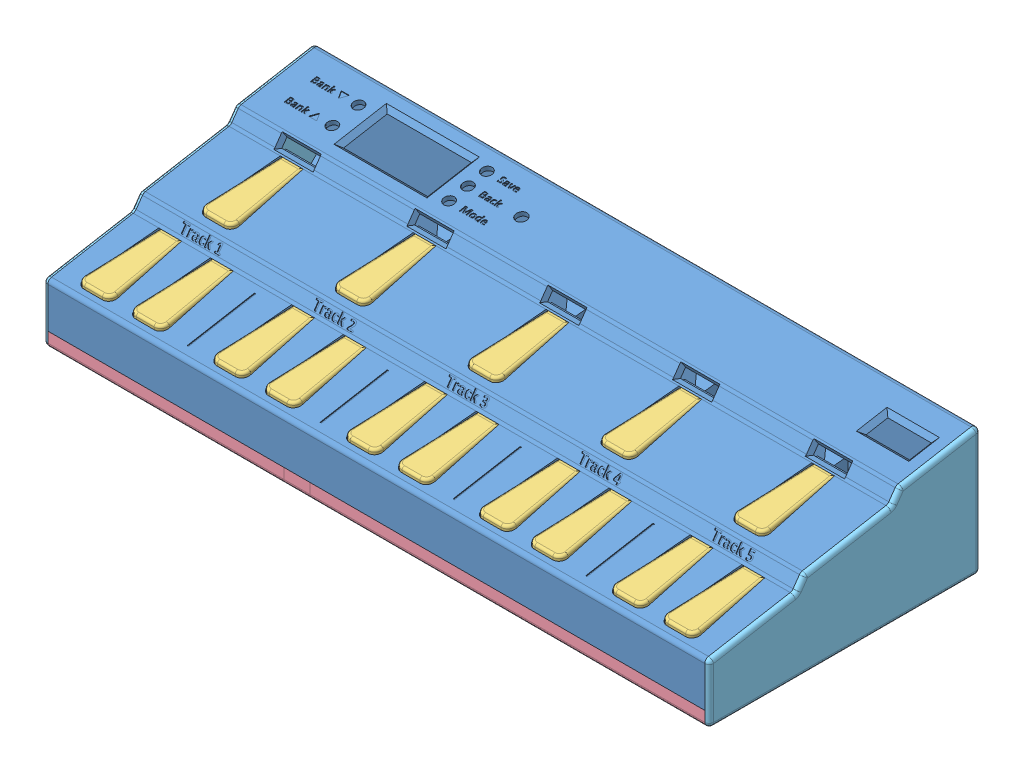
SolidWorks assembly Footpedal2, configuration Default. Lengths in mm.
Overall size (451 86.2 183.81).
49 component instances, 5 part files, 20 mates.
Components (placement in the parent):
- Top_Shell3-1: Top_Shell3 [Default] at (-376.4232 -4.088 58.5236) size (445 76.2 183.81)
- SwitschAssembly-1: SwitschAssembly [Default] at (-206.8501 9.3898 47.9079) x (1 0 0) z (0 -0.173648 0.984808) size (29.17 17.83 62)
  - SwitchHousing-1: SwitchHousing [Default] at (-144.5731 34.074 64.2085) size (29.17 13.5 62)
  - Part2^SwitschAssembly-1: Part2^SwitschAssembly [Default] at (-144.5731 29.574 41.0085) x (0 0.059044 0.998255) z (-1 0 0) size (55.8 14.56 22.57) (virtual)
- SwitschAssembly-2: SwitschAssembly [Default] at (-189.3501 28.0002 -16.9164) x (1 0 0) z (0 -0.173648 0.984808) size (29.17 17.83 62)
  - SwitchHousing-1: SwitchHousing [Default] at (-144.5731 34.074 64.2085) size (29.17 13.5 62)
  - Part2^SwitschAssembly-1: Part2^SwitschAssembly [Default] at (-144.5731 29.574 41.0085) x (0 0.059044 0.998255) z (-1 0 0) size (55.8 14.56 22.57) (virtual)
- SwitschAssembly-3: SwitschAssembly [Default] at (-171.8501 9.3898 47.9079) x (1 0 0) z (0 -0.173648 0.984808) size (29.17 17.83 62)
  - SwitchHousing-1: SwitchHousing [Default] at (-144.5731 34.074 64.2085) size (29.17 13.5 62)
  - Part2^SwitschAssembly-1: Part2^SwitschAssembly [Default] at (-144.5731 29.574 41.0085) x (0 0.059044 0.998255) z (-1 0 0) size (55.8 14.56 22.57) (virtual)
- SwitschAssembly-4: SwitschAssembly [Default] at (-99.3501 28.0002 -16.9164) x (1 0 0) z (0 -0.173648 0.984808) size (29.17 17.83 62)
  - SwitchHousing-1: SwitchHousing [Default] at (-144.5731 34.074 64.2085) size (29.17 13.5 62)
  - Part2^SwitschAssembly-1: Part2^SwitschAssembly [Default] at (-144.5731 29.574 41.0085) x (0 0.059044 0.998255) z (-1 0 0) size (55.8 14.56 22.57) (virtual)
- SwitschAssembly-5: SwitschAssembly [Default] at (-9.3501 28.0002 -16.9164) x (1 0 0) z (0 -0.173648 0.984808) size (29.17 17.83 62)
  - SwitchHousing-1: SwitchHousing [Default] at (-144.5731 34.074 64.2085) size (29.17 13.5 62)
  - Part2^SwitschAssembly-1: Part2^SwitschAssembly [Default] at (-144.5731 29.574 41.0085) x (0 0.059044 0.998255) z (-1 0 0) size (55.8 14.56 22.57) (virtual)
- SwitschAssembly-6: SwitschAssembly [Default] at (80.6499 28.0002 -16.9164) x (1 0 0) z (0 -0.173648 0.984808) size (29.17 17.83 62)
  - SwitchHousing-1: SwitchHousing [Default] at (-144.5731 34.074 64.2085) size (29.17 13.5 62)
  - Part2^SwitschAssembly-1: Part2^SwitschAssembly [Default] at (-144.5731 29.574 41.0085) x (0 0.059044 0.998255) z (-1 0 0) size (55.8 14.56 22.57) (virtual)
- SwitschAssembly-7: SwitschAssembly [Default] at (170.6499 28.0002 -16.9164) x (1 0 0) z (0 -0.173648 0.984808) size (29.17 17.83 62)
  - SwitchHousing-1: SwitchHousing [Default] at (-144.5731 34.074 64.2085) size (29.17 13.5 62)
  - Part2^SwitschAssembly-1: Part2^SwitschAssembly [Default] at (-144.5731 29.574 41.0085) x (0 0.059044 0.998255) z (-1 0 0) size (55.8 14.56 22.57) (virtual)
- SwitschAssembly-8: SwitschAssembly [Default] at (-81.8501 9.3898 47.9079) x (1 0 0) z (0 -0.173648 0.984808) size (29.17 17.83 62)
  - SwitchHousing-1: SwitchHousing [Default] at (-144.5731 34.074 64.2085) size (29.17 13.5 62)
  - Part2^SwitschAssembly-1: Part2^SwitschAssembly [Default] at (-144.5731 29.574 41.0085) x (0 0.059044 0.998255) z (-1 0 0) size (55.8 14.56 22.57) (virtual)
- SwitschAssembly-9: SwitschAssembly [Default] at (8.1499 9.3898 47.9079) x (1 0 0) z (0 -0.173648 0.984808) size (29.17 17.83 62)
  - SwitchHousing-1: SwitchHousing [Default] at (-144.5731 34.074 64.2085) size (29.17 13.5 62)
  - Part2^SwitschAssembly-1: Part2^SwitschAssembly [Default] at (-144.5731 29.574 41.0085) x (0 0.059044 0.998255) z (-1 0 0) size (55.8 14.56 22.57) (virtual)
- SwitschAssembly-10: SwitschAssembly [Default] at (98.1499 9.3898 47.9079) x (1 0 0) z (0 -0.173648 0.984808) size (29.17 17.83 62)
  - SwitchHousing-1: SwitchHousing [Default] at (-144.5731 34.074 64.2085) size (29.17 13.5 62)
  - Part2^SwitschAssembly-1: Part2^SwitschAssembly [Default] at (-144.5731 29.574 41.0085) x (0 0.059044 0.998255) z (-1 0 0) size (55.8 14.56 22.57) (virtual)
- SwitschAssembly-11: SwitschAssembly [Default] at (188.1499 9.3898 47.9079) x (1 0 0) z (0 -0.173648 0.984808) size (29.17 17.83 62)
  - SwitchHousing-1: SwitchHousing [Default] at (-144.5731 34.074 64.2085) size (29.17 13.5 62)
  - Part2^SwitschAssembly-1: Part2^SwitschAssembly [Default] at (-144.5731 29.574 41.0085) x (0 0.059044 0.998255) z (-1 0 0) size (55.8 14.56 22.57) (virtual)
- SwitschAssembly-12: SwitschAssembly [Default] at (-116.8501 9.3898 47.9079) x (1 0 0) z (0 -0.173648 0.984808) size (29.17 17.83 62)
  - SwitchHousing-1: SwitchHousing [Default] at (-144.5731 34.074 64.2085) size (29.17 13.5 62)
  - Part2^SwitschAssembly-1: Part2^SwitschAssembly [Default] at (-144.5731 29.574 41.0085) x (0 0.059044 0.998255) z (-1 0 0) size (55.8 14.56 22.57) (virtual)
- SwitschAssembly-13: SwitschAssembly [Default] at (-26.8501 9.3898 47.9079) x (1 0 0) z (0 -0.173648 0.984808) size (29.17 17.83 62)
  - SwitchHousing-1: SwitchHousing [Default] at (-144.5731 34.074 64.2085) size (29.17 13.5 62)
  - Part2^SwitschAssembly-1: Part2^SwitschAssembly [Default] at (-144.5731 29.574 41.0085) x (0 0.059044 0.998255) z (-1 0 0) size (55.8 14.56 22.57) (virtual)
- SwitschAssembly-14: SwitschAssembly [Default] at (63.1499 9.3898 47.9079) x (1 0 0) z (0 -0.173648 0.984808) size (29.17 17.83 62)
  - SwitchHousing-1: SwitchHousing [Default] at (-144.5731 34.074 64.2085) size (29.17 13.5 62)
  - Part2^SwitschAssembly-1: Part2^SwitschAssembly [Default] at (-144.5731 29.574 41.0085) x (0 0.059044 0.998255) z (-1 0 0) size (55.8 14.56 22.57) (virtual)
- SwitschAssembly-15: SwitschAssembly [Default] at (153.1499 9.3898 47.9079) x (1 0 0) z (0 -0.173648 0.984808) size (29.17 17.83 62)
  - SwitchHousing-1: SwitchHousing [Default] at (-144.5731 34.074 64.2085) size (29.17 13.5 62)
  - Part2^SwitschAssembly-1: Part2^SwitschAssembly [Default] at (-144.5731 29.574 41.0085) x (0 0.059044 0.998255) z (-1 0 0) size (55.8 14.56 22.57) (virtual)
- Base2-1: Base2 [Default] at (-46.4486 6.1315 -0.7339) size (445 13 183.81)
- SidePlate2-1: SidePlate2 [Left] at origin size (6 86.2 183.81)
- SidePlate2-2: SidePlate2 [Right] at (439 0 0) size (6 86.2 183.81)
Mates (geometry in assembly coordinates):
- Concentric3: concentric: cylinder of Top_Shell3-1 through (-341.2011 31.3289 102.5921) axis (-1 0 0) radius 1.5; cylinder of ? through (-339.2011 31.3289 102.5921) axis (-1 0 0) radius 1.5
- Coincident2: coincident: plane of Top_Shell3-1 through (-361.2011 28.4098 98.788) normal (-1 0 0); plane of ? through (-361.2011 57.7757 152.1774) normal (1 0 0)
- Concentric4: concentric: cylinder of Top_Shell3-1 through (-341.2011 41.173 104.3564) axis (-1 0 0) radius 1.5; cylinder of ? through (-339.2011 41.173 104.3564) axis (-1 0 0) radius 1.5
- Coincident7: coincident: plane of assembly; plane of assembly; plane of Top_Shell3-1 through (-351.4232 31.7964 117.0578) normal (0 0.984808 0.173648); plane of SwitschAssembly-1/SwitchHousing-1 through (-351.4232 31.7964 117.0578) normal (0 0.984808 0.173648)
- Coincident6: coincident: plane of assembly; plane of assembly; plane of Top_Shell3-1 through (-351.4232 -4.088 58.5236) normal (-1 0 0); plane of SwitschAssembly-1/SwitchHousing-1 through (-351.4232 31.7964 117.0578) normal (1 0 0)
- Coincident9: coincident: line of assembly; line of assembly; line of Top_Shell3-1 through (68.5768 36.1151 92.5653) axis (-1 0 0); line of SwitschAssembly-1/SwitchHousing-1 through (-359.1579 36.1151 92.5653) axis (1 0 0)
- Coincident11: coincident: plane of Top_Shell3-1 through (68.5768 44.5224 83.1437) normal (0 0.984808 0.173648); plane of ? through (-333.9232 50.4068 49.7715) normal (0 0.984808 0.173648)
- Coincident13: coincident: point of Top_Shell3-1; unknown of ?
- Coincident14: coincident: line of Top_Shell3-1 through (-325.5593 54.7255 25.279) axis (-1 0 0); line of ? through (-341.6579 54.7255 25.279) axis (1 0 0)
- Coincident15: coincident: plane of assembly; plane of assembly; plane of Top_Shell3-1 through (68.5768 44.5224 85.6058) normal (0 0.984808 0.173648); plane of SwitschAssembly-2/SwitchHousing-1 through (-333.9232 50.4068 52.2336) normal (0 0.984808 0.173648)
- Coincident16: coincident: line of assembly; point of assembly; line of Top_Shell3-1 through (-333.9232 44.5224 85.6058) axis (0 -0.173648 0.984808); point of SwitschAssembly-2/SwitchHousing-1
- Coincident17: coincident: line of assembly; line of assembly; line of Top_Shell3-1 through (-341.6579 54.7255 27.7411) axis (-1 0 0); line of SwitschAssembly-2/SwitchHousing-1 through (-341.6579 54.7255 27.7411) axis (1 0 0)
- Concentric5: concentric: cylinder of assembly; cylinder of assembly; cylinder of Top_Shell3-1 through (-372.8232 1.912 -26.7829) axis (0 -1 0) radius 2.6; cylinder of Base2-1 through (-372.8232 -14.088 -26.7829) axis (0 -1 0) radius 1.75
- Coincident18: coincident: plane of assembly; plane of assembly; plane of Top_Shell3-1 through (68.5768 -4.088 -30.3829) normal (0 -1 0); plane of Base2-1 through (68.5768 -4.088 -30.3829) normal (0 1 0)
- Coincident19: coincident: plane of assembly; plane of assembly; plane of Top_Shell3-1 through (-376.4232 -4.088 58.5236) normal (-1 0 0); plane of Base2-1 through (-376.4232 6.1315 -0.7339) normal (-1 0 0)
- Coincident20: coincident: plane of Top_Shell3-1 through (68.5768 -4.088 58.5236) normal (1 0 0); plane of ? through (68.5768 6.1315 -93.953) normal (-1 0 0)
- Coincident21: coincident: line of Base2-1 through (68.5768 -14.088 -30.3829) axis (0 0 1); line of ? through (68.5768 -14.088 -123.602) axis (0 0 1)
- Coincident23: coincident: plane of assembly; plane of assembly; plane of Top_Shell3-1 through (68.5768 -4.088 58.5236) normal (1 0 0); plane of SidePlate2-2 through (68.5768 69.1082 -30.3829) normal (-1 0 0)
- Coincident24: coincident: line of assembly; line of assembly; line of Top_Shell3-1 through (68.5768 23.3947 150.43) axis (0 -1 0); line of SidePlate2-2 through (68.5768 -11.088 150.43) axis (0 1 0)
- Coincident25: coincident: line of assembly; line of assembly; line of Top_Shell3-1 through (68.5768 36.1151 92.5653) axis (0 -0.173648 0.984808); line of SidePlate2-2 through (68.5768 26.3491 147.9509) axis (0 0.173648 -0.984808)
